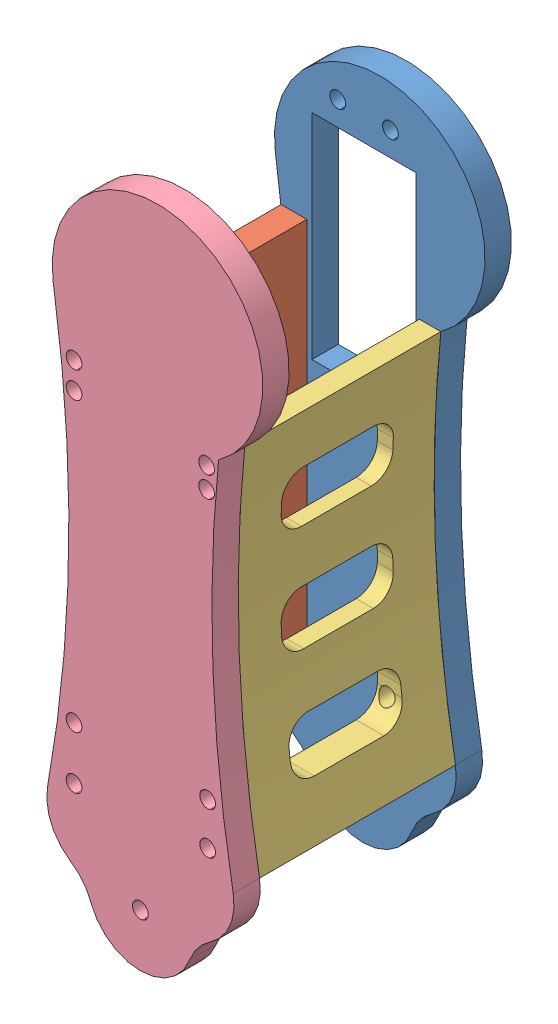
SolidWorks assembly JuntaPrincpal, configuration Valor predeterminado. Lengths in mm.
Overall size (41.02 127.72 47.2).
4 component instances, 4 part files, 9 mates.
Components (placement in the parent):
- TT DIREITA-1: TT DIREITA [Valor predeterminado] at (-20.4895 -55.6066 125.2156) size (41.02 127.72 5)
- H1-1: H1 [Valor predeterminado] at (-20.4895 -55.6066 130.2156) size (7.02 75.61 37.2)
- H2-1: H2 [Valor predeterminado] at (-20.4895 -55.6066 130.2156) size (6.85 69.87 37.2)
- TT ESQUERDA-1: TT ESQUERDA [Valor predeterminado] at (-20.4895 -55.6066 167.4156) size (41.02 127.72 5)
Mates (geometry in assembly coordinates):
- Coincidente1: coincident anti-aligned: plane of TT DIREITA-1 through (-20.4895 -55.6066 130.2156) normal (0 0 1); plane of H2-1 through (-20.4895 -55.6066 130.2156) normal (0 0 -1)
- Coincidente2: coincident aligned: circle of TT DIREITA-1; circle of H2-1
- Coincidente3: coincident anti-aligned: plane of TT DIREITA-1 through (-20.4895 -55.6066 130.2156) normal (0 0 1); plane of H1-1 through (-20.4895 -55.6066 130.2156) normal (0 0 -1)
- Concêntrico1: concentric aligned: cylinder of TT DIREITA-1 through (-284.0586 0.7323 130.2156) axis (0 0 -1) radius 250; cylinder of H1-1 through (-284.0586 0.7323 167.4156) axis (0 0 -1) radius 250
- Coincidente5: coincident: line of TT DIREITA-1 through (-2.874 -44.0649 130.2156) axis (0 0 -1); plane of H2-1 through (-54.8556 -44.0649 130.2156) normal (0 -1 0)
- Coincidente6: coincident aligned: plane of H1-1 through (-54.8556 -44.0649 130.2156) normal (0 -1 0); plane of H2-1 through (-54.8556 -44.0649 130.2156) normal (0 -1 0)
- Coincidente7: coincident anti-aligned: plane of H1-1 through (-20.4895 -55.6066 167.4156) normal (0 0 1); plane of TT ESQUERDA-1 through (-20.4895 -55.6066 167.4156) normal (0 0 -1)
- Concêntrico2: concentric aligned: circle of TT DIREITA-1; circle of TT ESQUERDA-1
- Concêntrico3: concentric aligned: circle of TT DIREITA-1; circle of TT ESQUERDA-1
